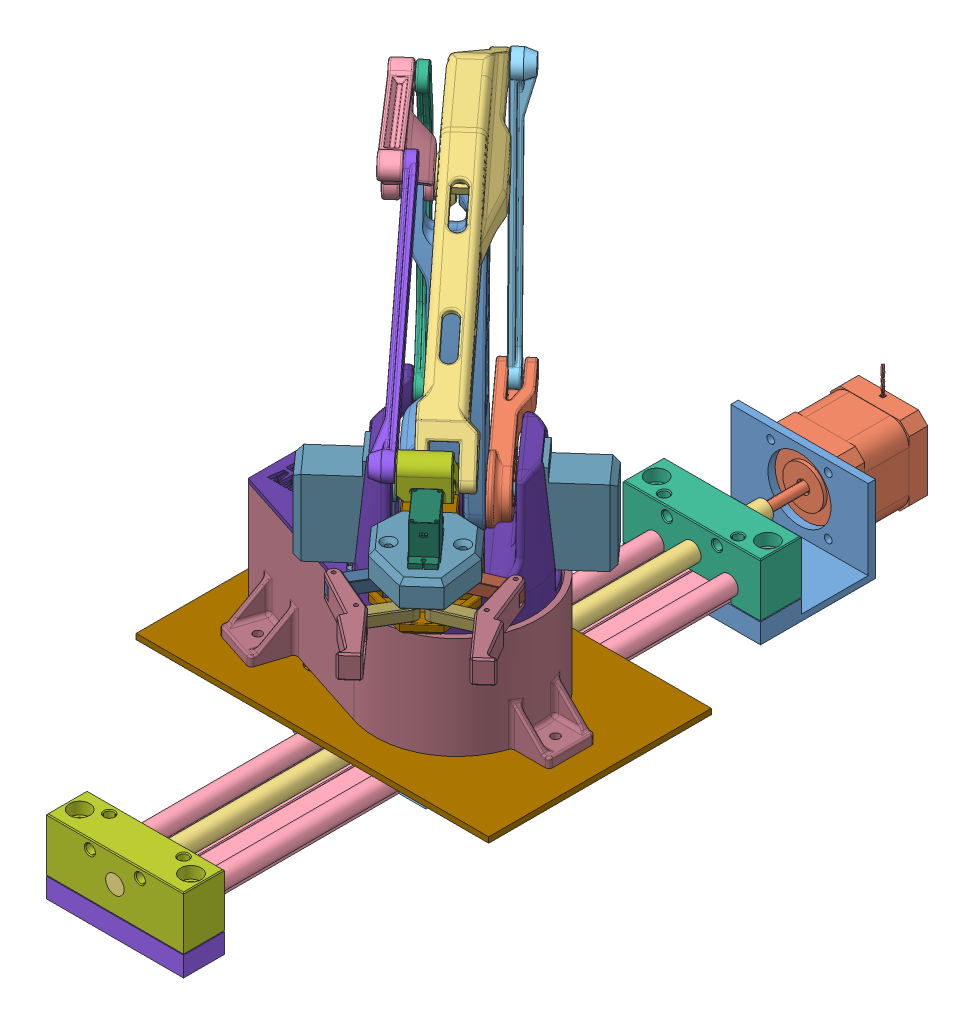
SolidWorks assembly Todo, configuration Predeterminado. Lengths in mm.
Overall size (627.36 318.62 751.93).
69 component instances, 35 part files, 14 mates.
Components (placement in the parent):
- Soporte_motor-1: Soporte_motor [Predeterminado] at (-8.4955 -0.7307 43) size (74 46.3 62)
- Stepper Motor-1: Stepper Motor [Default] at (-8.4955 -0.7307 -1) x (0 0 1) z (-1 0 0) size (77.9 47.49 42.3)
- SLW-1040-06-220-1: SLW-1040-06-220 [Predeterminado] at (-8.4955 -15.2307 416) x (1 0 0) z (0 1 0) size (74 350 29)
  - 2023_03_02_09_07_04_0221-1: 2023_03_02_09_07_04_0221 [Predeterminado] at origin size (10 350 10)
  - 2023_03_02_09_07_04_0206-1: 2023_03_02_09_07_04_0206 [Predeterminado] at origin size (50 309 14)
  - 2023_03_02_09_07_04_0143-1: 2023_03_02_09_07_04_0143 [Predeterminado] at origin size (73 69 22.73)
  - 2023_03_02_09_07_04_0128-1: 2023_03_02_09_07_04_0128 [Predeterminado] at origin size (74 22 29)
  - 2023_03_02_09_07_04_0112-1: 2023_03_02_09_07_04_0112 [Predeterminado] at origin size (74 22 29)
- Soporte_Patin-2: Soporte_Patin [Predeterminado] at (-45.4955 -20.5557 423) x (0 0 -1) z (1 0 0) size (22 10.65 74)
- Base_Robot_Patin-3: Base_Robot_Patin [Predeterminado] at (28.0045 14.7693 284) x (-1 0 0) z (0 -1 0) size (190 120 9)
- Robot-1: Robot [Predeterminado] at (42.136 -114.9178 249.6002) x (1 0 0) z (0 1 0) size (627.36 692.16 274.97)
  - Base-1: Base [Predeterminado] at (-30.8185 -1.8998 132.6871) size (160.19 90.57 55)
    - 020 ball.step-1: 020 ball.step [Predeterminado] at (29.3993 9.5524 42.8783) x (0.309017 -0.951057 0) z (0 0 1) size (6 6 6)
    - 020 ball.step-2: 020 ball.step [Predeterminado] at (-27.9703 -13.1618 42.8783) x (-0.425779 0.904827 0) z (0 0 1) size (6 6 6)
    - MG946R_piattelo.step-1: MG946R_piattelo.step [Predeterminado] at (-56.3 0 45.9) size (20.5 20.5 5.7)
    - 020 ball.step-3: 020 ball.step [Predeterminado] at (18.1698 -25.0086 42.8783) x (-0.809017 -0.587785 0) z (0 0 1) size (6 6 6)
    - 020 ball.step-4: 020 ball.step [Predeterminado] at (-11.3796 -28.7415 42.8783) x (-0.929776 0.368125 0) z (0 0 1) size (6 6 6)
    - 020 ball.step-5: 020 ball.step [Predeterminado] at (7.6876 29.9411 42.8783) x (0.968583 -0.24869 0) z (0 0 1) size (6 6 6)
    - 010_gearservo.step-1: 010_gearservo.step [Predeterminado] at (-56.3 -0.75 44.45) x (0 1 0) z (-1 0 0) size (40.71 5.06 40.95)
    - 020 ball.step-6: 020 ball.step [Predeterminado] at (-30.3647 -5.7924 42.8783) x (-0.187381 0.982287 0) z (0 0 1) size (6 6 6)
    - 020 ball.step-7: 020 ball.step [Predeterminado] at (-23.8183 -19.7042 42.8783) x (-0.637424 0.770513 0) z (0 0 1) size (6 6 6)
    - 020 ball.step-8: 020 ball.step [Predeterminado] at (-29.3993 9.5524 42.8783) x (0.309017 0.951057 0) z (0 0 1) size (6 6 6)
    - 020 ball.step-9: 020 ball.step [Predeterminado] at (14.8921 27.0886 42.8783) x (0.876307 -0.481754 0) z (0 0 1) size (6 6 6)
    - 020 ball.step-10: 020 ball.step [Predeterminado] at (23.8183 -19.7042 42.8783) x (-0.637424 -0.770513 0) z (0 0 1) size (6 6 6)
    - 020 ball.step-11: 020 ball.step [Predeterminado] at (-3.8743 -30.6685 42.8783) x (-0.992115 0.125333 0) z (0 0 1) size (6 6 6)
    - 020 ball.step-12: 020 ball.step [Predeterminado] at (-18.1698 -25.0086 42.8783) x (-0.809017 0.587785 0) z (0 0 1) size (6 6 6)
    - 020 ball.step-13: 020 ball.step [Predeterminado] at (30.8513 1.941 42.8783) x (0.062791 -0.998027 0) z (0 0 1) size (6 6 6)
    - 020 ball.step-14: 020 ball.step [Predeterminado] at (30.3647 -5.7924 42.8783) x (-0.187381 -0.982287 0) z (0 0 1) size (6 6 6)
    - 020 ball.step-15: 020 ball.step [Predeterminado] at (-14.8921 27.0886 42.8783) x (0.876307 0.481754 0) z (0 0 1) size (6 6 6)
    - 012_base.step-1: 012_base.step [Predeterminado] at origin size (160.19 90.57 55)
    - 020 ball.step-16: 020 ball.step [Predeterminado] at (3.8743 -30.6685 42.8783) x (-0.992115 -0.125333 0) z (0 0 1) size (6 6 6)
    - 020 ball.step-17: 020 ball.step [Predeterminado] at (11.3796 -28.7415 42.8783) x (-0.929776 -0.368125 0) z (0 0 1) size (6 6 6)
    - MG946R.step-1: MG946R.step [Predeterminado] at (-66.05 0 8.5) size (54.5 20 43.3)
    - 020 ball.step-18: 020 ball.step [Predeterminado] at (27.9703 -13.1618 42.8783) x (-0.425779 -0.904827 0) z (0 0 1) size (6 6 6)
    - 020 ball.step-19: 020 ball.step [Predeterminado] at (26.1001 16.5636 42.8783) x (0.535827 -0.844328 0) z (0 0 1) size (6 6 6)
    - 020 ball.step-20: 020 ball.step [Predeterminado] at (0 30.9123 42.8783) size (6 6 6)
    - 020 ball.step-21: 020 ball.step [Predeterminado] at (-21.1609 22.5341 42.8783) x (0.728969 0.684547 0) z (0 0 1) size (6 6 6)
    - 020 ball.step-22: 020 ball.step [Predeterminado] at (-7.6876 29.9411 42.8783) x (0.968583 0.24869 0) z (0 0 1) size (6 6 6)
    - 020 ball.step-23: 020 ball.step [Predeterminado] at (-26.1001 16.5636 42.8783) x (0.535827 0.844328 0) z (0 0 1) size (6 6 6)
    - 013 lower base.step-1: 013 lower base.step [Predeterminado] at (0 0 34) size (85.8 81.6 8)
    - 020 ball.step-24: 020 ball.step [Predeterminado] at (-30.8513 1.941 42.8783) x (0.062791 0.998027 0) z (0 0 1) size (6 6 6)
    - 606.step-1: 606.step [Predeterminado] at (0 0 37) size (17 17 6)
    - 020 ball.step-25: 020 ball.step [Predeterminado] at (21.1609 22.5341 42.8783) x (0.728969 -0.684547 0) z (0 0 1) size (6 6 6)
  - Rotor base.step-1: Rotor base.step [Predeterminado] at (-30.8185 -1.8998 184.1371) x (-0.747541 -0.664216 0) z (0 0 1) size (124 85.97 83.76)
    - 001_base.step-1: 001_base.step [Predeterminado] at origin size (80 85.97 72.76)
    - MG946R.step-1: MG946R.step [Predeterminado] at (-55.5 0 33.5) x (0 0 1) z (1 0 0) size (54.5 20 43.3)
    - 011_gearmast.step-1: 011_gearmast.step [Predeterminado] at (0 0 -7) x (0 1 0) z (-1 0 0) size (77.97 11.02 78.03)
    - MG946R.step-2: MG946R.step [Predeterminado] at (55.5 0 33.5) x (0 0 1) z (-1 0 0) size (54.5 20 43.3)
  - Columna.step-2: Columna.step [Predeterminado] at (-34.3694 -5.0548 227.1371) x (-0.660457 0.74331 -0.106239) z (-0.070565 0.079418 0.994341) size (39.1 33.03 161)
  - Tensor_espiga_brazo.step-2: Tensor_espiga_brazo.step [Predeterminado] at (-22.0349 5.9047 227.1371) x (-0.637928 0.717956 0.278545) z (0.747541 0.664216 0) size (78 30 16.07)
  - Brazo.step-3: Brazo.step [Predeterminado] at (-35.6727 12.9729 361.3731) x (0.637928 -0.717956 -0.278545) z (0.185014 -0.208224 0.960423) size (215 28.81 39.31)
  - Triangulo_equilibrador.step-1: Triangulo_equilibrador.step [Predeterminado] at (-54.735 -3.9645 361.3731) x (0.660144 -0.742958 0.11056) z (-0.073436 0.082648 0.993869) size (84 20.08 40.26)
  - Espiga_brazo.step-1: Espiga_brazo.step [Predeterminado] at (-59.8334 55.1447 310.1322) x (0.070565 -0.079418 -0.994341) z (0.747541 0.664216 0) size (148 13 10.81)
  - Espiga_Equilibradora.step-1: Espiga_Equilibradora.step [Predeterminado] at (-70.6679 23.0755 314.4454) x (0.070541 -0.07939 -0.994345) z (-0.747541 -0.664216 0) size (148 26.5 5.5)
  - Soporte_brazo.step-1: Soporte_brazo.step [Predeterminado] at (85.7091 -120.6251 313.9972) x (0.747541 0.664216 0) z (-0.001187 0.001336 0.999998) size (22 45.8 41.5)
  - Espiga_brazo_fin.step-1: Espiga_brazo_fin.step [Predeterminado] at (17.967 -77.5065 369.1995) x (-0.638603 0.718715 0.27502) z (-0.747541 -0.664216 0) size (160 13 10.81)
  - Garra-1: Garra [Predeterminado] at (88.8455 -152.1106 266.1231) x (-0.747541 -0.664216 0) z (-0.001187 0.001336 0.999998) size (78.48 855.85 189.81)
    - EEZYbotARM Palm.step-1: EEZYbotARM Palm.step [Predeterminado] at (-9.8569 4.5901 44.9724) size (43.18 58.05 26.16)
    - Gear Arm Right.step-1: Gear Arm Right.step [Predeterminado] at (4.3671 1.1658 51.297) x (0.300645 -0.953736 0) z (0.953736 0.300645 0) size (18.76 9.54 40.35)
    - Gear Arm Left.step-1: Gear Arm Left.step [Predeterminado] at (-24.0809 1.1658 51.297) x (0.315898 0.948793 0) z (-0.948793 0.315898 0) size (18.68 6.36 40.27)
    - Forward Hinge Arm.step-1: Forward Hinge Arm.step [Predeterminado] at (-5.4119 22.3701 57.647) x (-0.300645 0.953736 0) z (0 0 -1) size (7.11 28.7 6.35)
    - Forward Hinge Arm.step-2: Forward Hinge Arm.step [Predeterminado] at (-14.3019 22.3701 51.297) x (0.315898 0.948793 0) z (0 0 1) size (7.11 28.7 6.35)
    - Finger.step-1: Finger.step [Predeterminado] at (10.6965 14.5224 47.995) size (17.82 57.24 12.7)
    - Finger.step-2: Finger.step [Predeterminado] at (-30.3035 14.8517 60.695) x (-1 0 0) z (0 0 -1) size (17.82 57.24 12.7)
    - EEZYbotARM Palm Top.step-1: EEZYbotARM Palm Top.step [Predeterminado] at (-9.8569 4.5901 61.1014) size (43.18 46.02 13.18)
    - sg90 micro servo-1: sg90 micro servo [Default] at (-15.7499 13.7849 62.8344) x (0 -1 0) z (1 0 0) size (855.85 189.81 11.8)
      - Part1-1: Part1 [Default] at (11.25 -26.7 0) size (855.85 189.81 11.8)
      - axis.step-1: axis.step [Default] at (5.9 3.2 5.9) x (0.296886 0 0.954913) z (0 -1 0) size (4.6 4.6 7.2)
  - Tapa.step-1: Tapa.step [Predeterminado] at (-30.8185 -1.8998 187.6871) size (76.28 78.06 8.05)
Mates (geometry in assembly coordinates):
- Coincidente1: coincident anti-aligned: plane of Soporte_motor-1 through (-8.4955 -0.7307 43) normal (0 0 -1); plane of Stepper Motor-1 through (-8.4955 -0.7307 43) normal (0 0 1)
- Concéntrica1: concentric aligned: cylinder of Soporte_motor-1 through (-8.4955 -0.7307 47) axis (0 0 -1) radius 17; cylinder of Stepper Motor-1 through (-8.4955 -0.7307 69) axis (0 0 -1) radius 2.5
- Coincidente2: coincident anti-aligned: plane of Soporte_motor-1 through (28.5045 -15.2307 105) normal (0 1 0); plane of SLW-1040-06-220-1/2023_03_02_09_07_04_0128-1 through (-8.4955 -15.2307 94) normal (0 -1 0)
- Concéntrica2: concentric anti-aligned: cylinder of Soporte_motor-1 through (21.5045 -25.8817 94) axis (0 1 0) radius 3.25; cylinder of SLW-1040-06-220-1/2023_03_02_09_07_04_0128-1 through (21.5045 -3.9307 94) axis (0 -1 0) radius 3.25
- Concéntrica3: concentric anti-aligned: cylinder of Soporte_motor-1 through (-38.4955 -25.8817 94) axis (0 1 0) radius 3.25; cylinder of SLW-1040-06-220-1/2023_03_02_09_07_04_0128-1 through (-38.4955 -3.9307 94) axis (0 -1 0) radius 3.25
- Coincidente3: coincident anti-aligned: plane of SLW-1040-06-220-1/2023_03_02_09_07_04_0112-1 through (-8.4955 -15.2307 405) normal (0 -1 0); plane of Soporte_Patin-2 through (28.5045 -15.2307 394) normal (0 1 0)
- Concéntrica4: concentric anti-aligned: cylinder of SLW-1040-06-220-1/2023_03_02_09_07_04_0112-1 through (-38.4955 -3.9307 405) axis (0 -1 0) radius 3.25; cylinder of Soporte_Patin-2 through (-38.4955 -25.8817 405) axis (0 1 0) radius 3.25
- Concéntrica5: concentric anti-aligned: cylinder of SLW-1040-06-220-1/2023_03_02_09_07_04_0112-1 through (21.5045 -3.9307 405) axis (0 -1 0) radius 3.25; cylinder of Soporte_Patin-2 through (21.5045 -25.8817 405) axis (0 1 0) radius 3.25
- Coincidente8: coincident: plane of SLW-1040-06-220-1/2023_03_02_09_07_04_0143-1 through (-37.4955 8.7693 284.001) normal (0 1 0); plane of Base_Robot_Patin-3 through (28.0045 8.7693 284) normal (0 -1 0)
- Concéntrica10: concentric: cylinder of SLW-1040-06-220-1/2023_03_02_09_07_04_0143-1 through (-38.4955 -3.8307 221.5) axis (0 1 0) radius 2.5; cylinder of Base_Robot_Patin-3 through (-38.4955 8.7693 221.5) axis (0 1 0) radius 3.1
- Concéntrica11: concentric aligned: cylinder of SLW-1040-06-220-1/2023_03_02_09_07_04_0143-1 through (-38.4955 -3.8307 277.5) axis (0 1 0) radius 2.5; cylinder of Base_Robot_Patin-3 through (-38.4955 8.7693 277.5) axis (0 1 0) radius 3.1
- Coincidente9: coincident: plane of Base_Robot_Patin-3 through (28.0045 17.7693 284) normal (0 1 0); plane of Robot-1/Base-1/012_base.step-1 through (-15.6825 17.7693 251.5) normal (0 -1 0)
- Concéntrica12: concentric: cylinder of Base_Robot_Patin-3 through (64.5045 17.7693 251.5) axis (0 -1 0) radius 2.25; cylinder of Robot-1/Base-1/012_base.step-1 through (64.5045 -169.3017 251.5) axis (0 1 0) radius 2.25
- Concéntrica13: concentric anti-aligned: cylinder of Base_Robot_Patin-3 through (-63.6187 17.7693 283.9307) axis (0 -1 0) radius 2.25; cylinder of Robot-1/Base-1/012_base.step-1 through (-63.6187 -169.3017 283.9307) axis (0 1 0) radius 2.25
